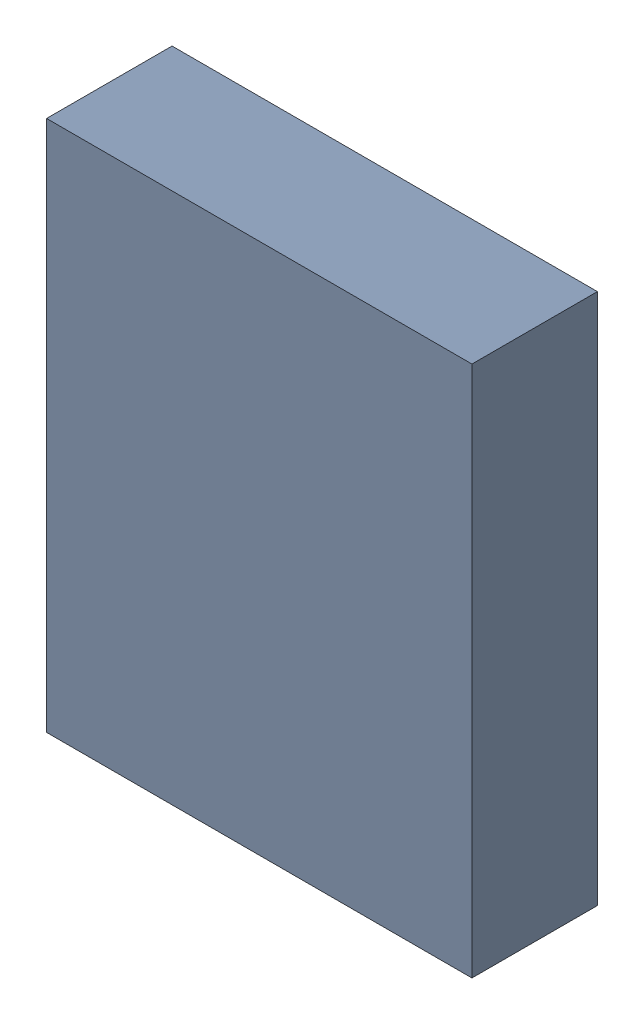
SolidWorks assembly L1, configuration Default. Lengths in mm.
Overall size (1 1.25 0.29).
2 component instances, 1 part files, 0 mates.
Components (placement in the parent):
- 870940800-1: 870940800 [Default] at (44.881 29.538 0.005) size (1 1.25 0.29)
  - Extruded_16-1: Extruded_16 [Default] at origin size (1 1.25 0.29)
